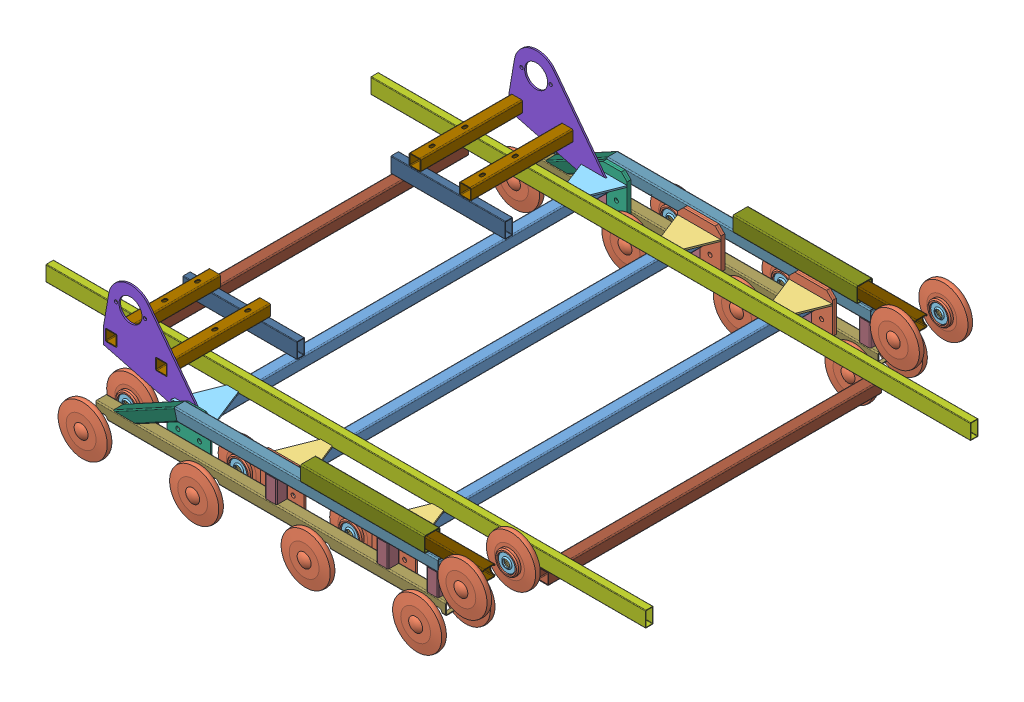
SolidWorks assembly ТП.016.001 - Рама гусеницы, configuration 00. Lengths in mm.
Overall size (1585 378.24 1275.68).
269 component instances, 35 part files, 9 mates.
Components (placement in the parent):
- ТП.016.01.01.01.00 - Рама корпуса-1: ТП.016.01.01.01.00 - Рама корпуса [00] x (-1 0 0) z (0 0 -1) size (1585 284.02 1098)
  - ТП.016.01.01.01.01.00 - Поперечная балка в сборе-1: ТП.016.01.01.01.01.00 - Поперечная балка в сборе [Центральная] at (824.8534 -30 544) size (112 110.77 1078)
    - ТП.016.01.01.01.01.01 - Поперечная балка (30х30)-1: ТП.016.01.01.01.01.01 - Поперечная балка (30х30) [--] at origin size (30 30 1068)
    - ТП.016.01.01.01.01.02 - Пластина кронштейна (5мм)-1: ТП.016.01.01.01.01.02 - Пластина кронштейна (5мм) [--] at (0 -56.7738 -5) size (112 110.77 5)
    - ТП.016.01.01.01.01.03 - Косынка верхняя (4мм)-1: ТП.016.01.01.01.01.03 - Косынка верхняя (4мм) [--] at (0 30 -10) size (112 4 104)
    - ТП.016.01.01.01.01.02 - Пластина кронштейна (5мм)-2: ТП.016.01.01.01.01.02 - Пластина кронштейна (5мм) [--] at (0 -56.7738 -1083) x (-1 0 0) z (0 0 -1) size (112 110.77 5)
    - ТП.016.01.01.01.01.03 - Косынка верхняя (4мм)-2: ТП.016.01.01.01.01.03 - Косынка верхняя (4мм) [--] at (0 30 -1078) x (-1 0 0) z (0 0 -1) size (112 4 104)
    - ТП.016.01.01.01.01.04 - Косынка нижняя (4мм)-2: ТП.016.01.01.01.01.04 - Косынка нижняя (4мм) [--] at (0 0 -1078) x (-1 0 0) z (0 0 -1) size (4 53.77 53.77)
    - ТП.016.01.01.01.01.04 - Косынка нижняя (4мм)-3: ТП.016.01.01.01.01.04 - Косынка нижняя (4мм) [--] at (0 0 -10) size (4 53.77 53.77)
    - ТП.016.01.01.01.01.05 - Пластина кронштейна задняя (5мм)-1: ТП.016.01.01.01.01.05 - Пластина кронштейна задняя (5мм) [--] at (0 -56.7738 -1083) x (-1 0 0) z (0 0 -1) size (112 110.77 5) (hidden)
    - ТП.016.01.01.01.01.06 - Косынка верхняя задняя (4мм)-1: ТП.016.01.01.01.01.06 - Косынка верхняя задняя (4мм) [--] at (-15 30 -1078) x (-1 0 0) z (0 0 -1) size (111.99 4 104) (hidden)
    - ТП.016.01.01.01.01.05 - Пластина кронштейна задняя (5мм)-2: ТП.016.01.01.01.01.05 - Пластина кронштейна задняя (5мм) [--] at (0 -56.7738 -10) x (-1 0 0) z (0 0 -1) size (112 110.77 5) (hidden)
    - ТП.016.01.01.01.01.06 - Косынка верхняя задняя (4мм)-2: ТП.016.01.01.01.01.06 - Косынка верхняя задняя (4мм) [--] at (-15 34 -10) x (-1 0 0) z (0 0 1) size (111.99 4 104) (hidden)
  - ТП.016.01.01.01.01.00 - Поперечная балка в сборе-2: ТП.016.01.01.01.01.00 - Поперечная балка в сборе [Центральная] at (536.5267 -30 544) size (112 110.77 1078)
    - ТП.016.01.01.01.01.01 - Поперечная балка (30х30)-1: ТП.016.01.01.01.01.01 - Поперечная балка (30х30) [--] at origin size (30 30 1068)
    - ТП.016.01.01.01.01.02 - Пластина кронштейна (5мм)-1: ТП.016.01.01.01.01.02 - Пластина кронштейна (5мм) [--] at (0 -56.7738 -5) size (112 110.77 5)
    - ТП.016.01.01.01.01.03 - Косынка верхняя (4мм)-1: ТП.016.01.01.01.01.03 - Косынка верхняя (4мм) [--] at (0 30 -10) size (112 4 104)
    - ТП.016.01.01.01.01.02 - Пластина кронштейна (5мм)-2: ТП.016.01.01.01.01.02 - Пластина кронштейна (5мм) [--] at (0 -56.7738 -1083) x (-1 0 0) z (0 0 -1) size (112 110.77 5)
    - ТП.016.01.01.01.01.03 - Косынка верхняя (4мм)-2: ТП.016.01.01.01.01.03 - Косынка верхняя (4мм) [--] at (0 30 -1078) x (-1 0 0) z (0 0 -1) size (112 4 104)
    - ТП.016.01.01.01.01.04 - Косынка нижняя (4мм)-2: ТП.016.01.01.01.01.04 - Косынка нижняя (4мм) [--] at (0 0 -1078) x (-1 0 0) z (0 0 -1) size (4 53.77 53.77)
    - ТП.016.01.01.01.01.04 - Косынка нижняя (4мм)-3: ТП.016.01.01.01.01.04 - Косынка нижняя (4мм) [--] at (0 0 -10) size (4 53.77 53.77)
    - ТП.016.01.01.01.01.05 - Пластина кронштейна задняя (5мм)-1: ТП.016.01.01.01.01.05 - Пластина кронштейна задняя (5мм) [--] at (0 -56.7738 -1083) x (-1 0 0) z (0 0 -1) size (112 110.77 5) (hidden)
    - ТП.016.01.01.01.01.06 - Косынка верхняя задняя (4мм)-1: ТП.016.01.01.01.01.06 - Косынка верхняя задняя (4мм) [--] at (-15 30 -1078) x (-1 0 0) z (0 0 -1) size (111.99 4 104) (hidden)
    - ТП.016.01.01.01.01.05 - Пластина кронштейна задняя (5мм)-2: ТП.016.01.01.01.01.05 - Пластина кронштейна задняя (5мм) [--] at (0 -56.7738 -10) x (-1 0 0) z (0 0 -1) size (112 110.77 5) (hidden)
    - ТП.016.01.01.01.01.06 - Косынка верхняя задняя (4мм)-2: ТП.016.01.01.01.01.06 - Косынка верхняя задняя (4мм) [--] at (-15 34 -10) x (-1 0 0) z (0 0 1) size (111.99 4 104) (hidden)
  - ТП.016.01.01.01.01.00 - Поперечная балка в сборе-3: ТП.016.01.01.01.01.00 - Поперечная балка в сборе [Задняя] at (1067.2668 -30 544) size (112 110.77 1078)
    - ТП.016.01.01.01.01.01 - Поперечная балка (30х30)-1: ТП.016.01.01.01.01.01 - Поперечная балка (30х30) [Под лебедку] at origin size (30 30 1068)
    - ТП.016.01.01.01.01.02 - Пластина кронштейна (5мм)-1: ТП.016.01.01.01.01.02 - Пластина кронштейна (5мм) [--] at (0 -56.7738 -5) size (112 110.77 5) (hidden)
    - ТП.016.01.01.01.01.03 - Косынка верхняя (4мм)-1: ТП.016.01.01.01.01.03 - Косынка верхняя (4мм) [--] at (0 30 -10) size (112 4 104) (hidden)
    - ТП.016.01.01.01.01.02 - Пластина кронштейна (5мм)-2: ТП.016.01.01.01.01.02 - Пластина кронштейна (5мм) [--] at (0 -56.7738 -1083) x (-1 0 0) z (0 0 -1) size (112 110.77 5) (hidden)
    - ТП.016.01.01.01.01.03 - Косынка верхняя (4мм)-2: ТП.016.01.01.01.01.03 - Косынка верхняя (4мм) [--] at (0 30 -1078) x (-1 0 0) z (0 0 -1) size (112 4 104) (hidden)
    - ТП.016.01.01.01.01.04 - Косынка нижняя (4мм)-2: ТП.016.01.01.01.01.04 - Косынка нижняя (4мм) [--] at (0 0 -1078) x (-1 0 0) z (0 0 -1) size (4 53.77 53.77)
    - ТП.016.01.01.01.01.04 - Косынка нижняя (4мм)-3: ТП.016.01.01.01.01.04 - Косынка нижняя (4мм) [--] at (0 0 -10) size (4 53.77 53.77)
    - ТП.016.01.01.01.01.05 - Пластина кронштейна задняя (5мм)-1: ТП.016.01.01.01.01.05 - Пластина кронштейна задняя (5мм) [--] at (0 -56.7738 -1083) x (-1 0 0) z (0 0 -1) size (112 110.77 5)
    - ТП.016.01.01.01.01.06 - Косынка верхняя задняя (4мм)-1: ТП.016.01.01.01.01.06 - Косынка верхняя задняя (4мм) [--] at (-15 30 -1078) x (-1 0 0) z (0 0 -1) size (111.99 4 104)
    - ТП.016.01.01.01.01.05 - Пластина кронштейна задняя (5мм)-2: ТП.016.01.01.01.01.05 - Пластина кронштейна задняя (5мм) [--] at (0 -56.7738 -10) x (-1 0 0) z (0 0 -1) size (112 110.77 5)
    - ТП.016.01.01.01.01.06 - Косынка верхняя задняя (4мм)-2: ТП.016.01.01.01.01.06 - Косынка верхняя задняя (4мм) [--] at (-15 34 -10) x (-1 0 0) z (0 0 1) size (111.99 4 104)
  - ТП.016.01.01.01.02 - Балка платформы боковая (40х20)-1: ТП.016.01.01.01.02 - Балка платформы боковая (40х20) [--] at (250 0 -420) x (0 0 -1) z (1 0 0) size (20 40 1550)
  - ТП.016.01.01.01.02 - Балка платформы боковая (40х20)-2: ТП.016.01.01.01.02 - Балка платформы боковая (40х20) [--] at (250 0 420) x (0 0 -1) z (1 0 0) size (20 40 1550)
  - Схема рамы ЭСКИЗ-1: Схема рамы ЭСКИЗ [--] x (0 0 -1) z (1 0 0) size (559 0 1052.27)
  - ТП.016.01.01.01.03.00 - Опора редуктора-1: ТП.016.01.01.01.03.00 - Опора редуктора [Правая] at (1235 143.2262 -526.5) x (-1 0 0) z (0 0 -1) size (276.73 227.25 267.34)
    - ТП.016.01.01.01.03.01 - Щека ведущей оси (4мм)-1: ТП.016.01.01.01.03.01 - Щека ведущей оси (4мм) [--] at origin size (249.73 227.25 4)
    - ТП.016.01.01.01.03.02 - Балка опоры ребуктора (30х30)-1: ТП.016.01.01.01.03.02 - Балка опоры ребуктора (30х30) [--] at (65 -72 0) size (30 30 267.34)
    - ТП.016.01.01.01.03.02 - Балка опоры ребуктора (30х30)-2: ТП.016.01.01.01.03.02 - Балка опоры ребуктора (30х30) [--] at (-65 -72 0) size (30 30 267.34)
    - ТП.016.01.01.01.03.02 - Балка опоры ребуктора (30х30)-3: ТП.016.01.01.01.03.02 - Балка опоры ребуктора (30х30) [--] at (95 -72 -4) x (-1 0 0) z (0 0 -1) size (30 30 267.34) (hidden)
    - ТП.016.01.01.01.03.02 - Балка опоры ребуктора (30х30)-4: ТП.016.01.01.01.03.02 - Балка опоры ребуктора (30х30) [--] at (-35 -72 -4) x (-1 0 0) z (0 0 -1) size (30 30 267.34) (hidden)
    - ТП.016.01.01.01.03.03 - Пол под редуктор (3мм)-1: ТП.016.01.01.01.03.03 - Пол под редуктор (3мм) [--] at (65 -143.2262 -181.9182) x (0 0 -1) z (1 0 0) size (130.84 76.23 264.73)
  - ТП.016.01.01.01.03.00 - Опора редуктора-2: ТП.016.01.01.01.03.00 - Опора редуктора [Левая] at (1235 143.2262 522.5) x (-1 0 0) z (0 0 -1) size (276.73 227.25 267.34)
    - ТП.016.01.01.01.03.01 - Щека ведущей оси (4мм)-1: ТП.016.01.01.01.03.01 - Щека ведущей оси (4мм) [--] at origin size (249.73 227.25 4)
    - ТП.016.01.01.01.03.02 - Балка опоры ребуктора (30х30)-1: ТП.016.01.01.01.03.02 - Балка опоры ребуктора (30х30) [--] at (65 -72 0) size (30 30 267.34) (hidden)
    - ТП.016.01.01.01.03.02 - Балка опоры ребуктора (30х30)-2: ТП.016.01.01.01.03.02 - Балка опоры ребуктора (30х30) [--] at (-65 -72 0) size (30 30 267.34) (hidden)
    - ТП.016.01.01.01.03.02 - Балка опоры ребуктора (30х30)-3: ТП.016.01.01.01.03.02 - Балка опоры ребуктора (30х30) [--] at (95 -72 -4) x (-1 0 0) z (0 0 -1) size (30 30 267.34)
    - ТП.016.01.01.01.03.02 - Балка опоры ребуктора (30х30)-4: ТП.016.01.01.01.03.02 - Балка опоры ребуктора (30х30) [--] at (-35 -72 -4) x (-1 0 0) z (0 0 -1) size (30 30 267.34)
    - ТП.016.01.01.01.03.03 - Пол под редуктор (3мм)-1: ТП.016.01.01.01.03.03 - Пол под редуктор (3мм) [--] at (65 -143.2262 177.9182) x (0 0 -1) z (1 0 0) size (130.84 76.23 264.73)
  - ТП.016.01.01.01.04 - Опора короткая под редуктор (40х20)-1: ТП.016.01.01.01.04 - Опора короткая под редуктор (40х20) [--] at (1052.2668 0 -259.1637) x (0 0 -1) z (1 0 0) size (20 40 294.73)
  - ТП.016.01.01.01.04 - Опора короткая под редуктор (40х20)-2: ТП.016.01.01.01.04 - Опора короткая под редуктор (40х20) [--] at (1052.2668 0 279.1637) x (0 0 -1) z (1 0 0) size (20 40 294.73)
  - ТП.016.01.01.01.05 - Поперечина короткая (30х30)-1: ТП.016.01.01.01.05 - Поперечина короткая (30х30) [--] at (1347 0 0) size (30 30 860)
  - ТП.016.01.01.01.05 - Поперечина короткая (30х30)-2: ТП.016.01.01.01.05 - Поперечина короткая (30х30) [--] at (280 0 0) size (30 30 860)
  - ТП.016.01.01.01.06 - Поддержка центральная (40х20)-1: ТП.016.01.01.01.06 - Поддержка центральная (40х20) [--] at (45 -9.1741 -23) x (0 0 1) z (-1 0 0) size (20 40 596.53)
  - ТП.016.01.01.01.06 - Поддержка центральная (40х20)-2: ТП.016.01.01.01.06 - Поддержка центральная (40х20) [--] at (45 -9.1741 43) x (0 0 1) z (-1 0 0) size (20 40 596.53)
  - ТП.016.01.01.01.07 - Пол перед (3мм)-1: ТП.016.01.01.01.07 - Пол перед (3мм) [Правый] at (0 0 -410) x (0 0 -1) z (1 0 0) size (377 29.49 517.11)
  - ТП.016.01.01.01.07 - Пол перед (3мм)-2: ТП.016.01.01.01.07 - Пол перед (3мм) [Левый] at (0 0 -344) x (0 0 -1) z (1 0 0) size (754 29.49 517.11)
  - ТП.016.01.01.01.08 - Пол центр (2мм)-1: ТП.016.01.01.01.08 - Пол центр (2мм) [--] at (250 0 0) x (0 0 -1) z (1 0 0) size (820 12 817.27)
  - ТП.016.01.01.01.09 - Задний бампер (40х20)-1: ТП.016.01.01.01.09 - Задний бампер (40х20) [--] at (1570 0 0) size (20 40 860)
  - ТП.016.01.01.01.10 - Пол капота (3мм)-1: ТП.016.01.01.01.10 - Пол капота (3мм) [--] at (1550 0 0) x (0 0 1) z (-1 0 0) size (820 13 482.73)
  - Гайка (ГОСТ ISO 4032-2014)-1: Гайка (ГОСТ ISO 4032-2014) [Гайка М6 (ГОСТ ISO 4032)] at (153.1386 -2.6 64.0253) x (-0.998033 0 -0.062689) z (0 1 0) size (10 11.05 5.2)
  - Гайка (ГОСТ ISO 4032-2014)-2: Гайка (ГОСТ ISO 4032-2014) [Гайка М6 (ГОСТ ISO 4032)] at (403.0634 -2.6 70.156) x (-0.991964 0 0.126519) z (0 1 0) size (10 11.05 5.2)
  - Гайка (ГОСТ ISO 4032-2014)-3: Гайка (ГОСТ ISO 4032-2014) [Гайка М6 (ГОСТ ISO 4032)] at (672.9822 -2.6 76.7772) x (-0.941367 0 0.337385) z (0 1 0) size (10 11.05 5.2)
  - Гайка (ГОСТ ISO 4032-2014)-4: Гайка (ГОСТ ISO 4032-2014) [Гайка М6 (ГОСТ ISO 4032)] at (1021.6211 -2.6 85.3294) x (-0.83604 0 0.548669) z (0 1 0) size (10 11.05 5.2)
  - Гайка (ГОСТ ISO 4032-2014)-5: Гайка (ГОСТ ISO 4032-2014) [Гайка М6 (ГОСТ ISO 4032)] at (1021.6211 -2.6 -85.3294) x (-0.680834 0 0.732437) z (0 1 0) size (10 11.05 5.2)
  - Гайка (ГОСТ ISO 4032-2014)-6: Гайка (ГОСТ ISO 4032-2014) [Гайка М6 (ГОСТ ISO 4032)] at (672.9822 -2.6 -76.7772) x (-0.498939 0 0.866637) z (0 1 0) size (10 11.05 5.2)
  - Гайка (ГОСТ ISO 4032-2014)-7: Гайка (ГОСТ ISO 4032-2014) [Гайка М6 (ГОСТ ISO 4032)] at (403.0634 -2.6 -70.156) x (-0.323185 0 0.946336) z (0 1 0) size (10 11.05 5.2)
  - Гайка (ГОСТ ISO 4032-2014)-8: Гайка (ГОСТ ISO 4032-2014) [Гайка М6 (ГОСТ ISO 4032)] at (153.1386 -2.6 -64.0253) x (-0.182176 0 0.983266) z (0 1 0) size (10 11.05 5.2)
- ТП.016.02.00 - Гусеничный модуль в сборе-1: ТП.016.02.00 - Гусеничный модуль в сборе [Левый] at (-392.3634 -86.7738 -559) x (-1 0 0) z (0 0 -1) size (1147.02 302.71 157.68)
  - ТП.016.02.01.00 - Модуль гусеницы силовой-1: ТП.016.02.01.00 - Модуль гусеницы силовой [Левый] at origin size (904.98 176.07 133.68)
    - ТП.016.02.01.01.00 - Рама гусеницы с осями-1: ТП.016.02.01.01.00 - Рама гусеницы с осями [00] at origin size (904.98 176.07 133.68)
      - ТП.016.02.01.01.01 - Нижняя балка гуленицы (30х30)-1: ТП.016.02.01.01.01 - Нижняя балка гуленицы (30х30) [--] at origin size (904.98 30 30)
      - ТП.016.02.01.01.02(02) - Ось цельная 21_3мм-1: ТП.016.02.01.01.02(02) - Ось цельная 21_3мм [--] x (0 0 1) z (-1 0 0) size (133.68 21.3 21.3)
      - ТП.016.02.01.01.02(02) - Ось цельная 21_3мм-2: ТП.016.02.01.01.02(02) - Ось цельная 21_3мм [--] at (288.3267 0 0) x (0 0 1) z (-0.987351 0.158553 0) size (133.68 21.3 21.3)
      - ТП.016.02.01.01.02(02) - Ось цельная 21_3мм-3: ТП.016.02.01.01.02(02) - Ось цельная 21_3мм [--] at (576.6534 0 0) x (0 0 1) z (-0.959125 0.282984 0) size (133.68 21.3 21.3)
      - ТП.016.02.01.01.02(02) - Ось цельная 21_3мм-4: ТП.016.02.01.01.02(02) - Ось цельная 21_3мм [--] at (864.9801 0 0) x (0 0 1) z (-0.928571 0.371154 0) size (133.68 21.3 21.3)
      - ТП.016.02.01.01.03 - Связка балок гусеничного модуля-1: ТП.016.02.01.01.03 - Связка балок гусеничного модуля [--] at (0 86.7738 0) x (-1 0 0) z (0 0 -1) size (30 56.77 30)
      - ТП.016.02.01.01.03 - Связка балок гусеничного модуля-2: ТП.016.02.01.01.03 - Связка балок гусеничного модуля [--] at (129.1634 86.7738 0) x (-1 0 0) z (0 0 -1) size (30 56.77 30)
      - ТП.016.02.01.01.03 - Связка балок гусеничного модуля-3: ТП.016.02.01.01.03 - Связка балок гусеничного модуля [--] at (417.4901 86.7738 0) x (-1 0 0) z (0 0 -1) size (30 56.77 30)
      - ТП.016.02.01.01.04 - Верхняя балка рамы гусеницы-1: ТП.016.02.01.01.04 - Верхняя балка рамы гусеницы [--] at (0 136.7738 0) x (0 0 1) z (-1 0 0) size (30 30 682.14)
      - ТП.016.02.01.01.05 - Задняя косая-1: ТП.016.02.01.01.05 - Задняя косая [--] at (864.9801 0 -15) x (0 0 -1) z (0.877984 -0.478691 0) size (30 30 181.27)
      - ТП.016.02.01.01.06.00 - Стакан натяжителя-1: ТП.016.02.01.01.06.00 - Стакан натяжителя [00] at (30 136.7738 0) x (-1 0 0) z (0 0 -1) size (320 50.91 50.91)
        - ТП.016.02.01.01.06.01 - Рубашка штока ролика натяжного-1: ТП.016.02.01.01.06.01 - Рубашка штока ролика натяжного [--] at origin size (320 40 40)
        - ТП.016.02.01.01.06.02 - Гайка рубашки штока-1: ТП.016.02.01.01.06.02 - Гайка рубашки штока [--] at (-320 0 0) x (0 -0.713098 -0.701064) z (1 0 0) size (36 36 20)
    - ТП.016.01.01.01.01.02 - Пластина кронштейна (5мм)-1: ТП.016.01.01.01.01.02 - Пластина кронштейна (5мм) [--] at (144.1634 0 20) size (112 110.77 5) (hidden)
    - ТП.016.01.01.01.01.02 - Пластина кронштейна (5мм)-2: ТП.016.01.01.01.01.02 - Пластина кронштейна (5мм) [--] at (432.4901 0 20) size (112 110.77 5) (hidden)
    - ТП.016.01.01.01.01.05 - Пластина кронштейна задняя (5мм)-1: ТП.016.01.01.01.01.05 - Пластина кронштейна задняя (5мм) [--] at (674.9034 0 15) x (-1 0 0) z (0 0 -1) size (112 110.77 5) (hidden)
    - ТП.016.01.01.01.01.02 - Пластина кронштейна (5мм)-4: ТП.016.01.01.01.01.02 - Пластина кронштейна (5мм) [--] at (144.1634 0 -20) x (-1 0 0) z (0 0 -1) size (112 110.77 5)
    - ТП.016.01.01.01.01.02 - Пластина кронштейна (5мм)-6: ТП.016.01.01.01.01.02 - Пластина кронштейна (5мм) [--] at (432.4901 0 -20) x (-1 0 0) z (0 0 -1) size (112 110.77 5)
    - ТП.016.01.01.01.01.05 - Пластина кронштейна задняя (5мм)-2: ТП.016.01.01.01.01.05 - Пластина кронштейна задняя (5мм) [--] at (674.9034 0 -20) x (-1 0 0) z (0 0 -1) size (112 110.77 5)
  - ТП.016.02.02.00 - Натяжитель гусеницы-1: ТП.016.02.02.00 - Натяжитель гусеницы [00] at (-117 136.7738 0) x (-1 0 0) z (0 0 1) size (371.74 149.44 157.68)
    - ТП.016.02.02.01.00 - Толкатель натяжки-1: ТП.016.02.02.01.00 - Толкатель натяжки [00] at origin size (311.12 30 133.68)
      - ТП.016.02.02.01.01 - Шток натяжного ролика (30х30)-1: ТП.016.02.02.01.01 - Шток натяжного ролика (30х30) [--] at origin size (297.02 30 30)
      - ТП.016.02.01.01.02(02) - Ось цельная 21_3мм-1: ТП.016.02.01.01.02(02) - Ось цельная 21_3мм [--] x (0 0 1) z (-0.910058 0.41448 0) size (133.68 21.3 21.3)
      - ТП.016.02.02.01.02 - Заглушка штока-1: ТП.016.02.02.01.02 - Заглушка штока [--] at (-297.0168 0 0) x (0 -1 0) z (1 0 0) size (26 26 20)
    - Каток 129(47) в сборе-1: Каток 129(47) в сборе [00] at (0 0 62.8416) x (0 0 1) z (1 0 0) size (35.7 129 129)
      - Каток 129(47)-1: Каток 129(47) [--] at origin size (35 129 129)
      - Подшипник ГОСТ 8338-75 -1: Подшипник ГОСТ 8338-75  [Подшипник 204 ГОСТ 8338-75] at (-1 0 0) x (1 0 0) z (0 -0.327433 -0.944874) size (14 47 47)
      - Стопор внутренний до 165мм (ГОСТ 13943-86)-1: Стопор внутренний до 165мм (ГОСТ 13943-86) [Кольцо 47] at (-8 0 0) x (0 0.910839 0.412761) z (-1 0 0) size (49.5 51.2 1.7)
      - Сальник 47х20-1: Сальник 47х20 [--] at (-9.7 0 0) x (-1 0 0) z (0 0.937697 -0.347453) size (10 47 47)
    - Каток 129(47) в сборе-2: Каток 129(47) в сборе [00] at (0 0 -62.8416) x (0 0 -1) z (-0.173648 0.984808 0) size (35.7 129 129)
      - Каток 129(47)-1: Каток 129(47) [--] at origin size (35 129 129)
      - Подшипник ГОСТ 8338-75 -1: Подшипник ГОСТ 8338-75  [Подшипник 204 ГОСТ 8338-75] at (-1 0 0) x (1 0 0) z (0 -0.327433 -0.944874) size (14 47 47)
      - Стопор внутренний до 165мм (ГОСТ 13943-86)-1: Стопор внутренний до 165мм (ГОСТ 13943-86) [Кольцо 47] at (-8 0 0) x (0 0.910839 0.412761) z (-1 0 0) size (49.5 51.2 1.7)
      - Сальник 47х20-1: Сальник 47х20 [--] at (-9.7 0 0) x (-1 0 0) z (0 0.937697 -0.347453) size (10 47 47)
    - ТП.016.02.02.02 - Шайба оси-1: ТП.016.02.02.02 - Шайба оси [--] at (0 0 -66.3614) x (0 0 1) z (0.48394 0.875101 0) size (4 24 24)
    - Болты с шестигранной головкой кт.В (ГОСТ 7798-70)-1: Болты с шестигранной головкой кт.В (ГОСТ 7798-70) [Болт М6-6gx14(S10) ГОСТ 7798-77] at (0 0 -69.3416) x (0 0 1) z (0.143998 -0.989578 0) size (18 10.9 10)
    - ТП.016.02.02.02 - Шайба оси-2: ТП.016.02.02.02 - Шайба оси [--] at (0 0 66.3614) x (0 0 -1) z (0.777771 0.628548 0) size (4 24 24)
    - Болты с шестигранной головкой кт.В (ГОСТ 7798-70)-2: Болты с шестигранной головкой кт.В (ГОСТ 7798-70) [Болт М6-6gx14(S10) ГОСТ 7798-77] at (0 0 69.3416) x (0 0 -1) z (-0.999549 -0.030028 0) size (18 10.9 10)
  - ТП.016.02.03 - Винт натяжителя-1: ТП.016.02.03 - Винт натяжителя [--] at (350.0168 136.7738 0) x (0 -0.01927 -0.999814) z (-1 0 0) size (20 20 231.35)
  - Каток 129(47) в сборе-1: Каток 129(47) в сборе [00] at (0 0 -62.8416) x (0 0 -1) z (-0.261474 0.96521 0) size (35.7 129 129)
    - Каток 129(47)-1: Каток 129(47) [--] at origin size (35 129 129)
    - Подшипник ГОСТ 8338-75 -1: Подшипник ГОСТ 8338-75  [Подшипник 204 ГОСТ 8338-75] at (-1 0 0) x (1 0 0) z (0 -0.327433 -0.944874) size (14 47 47)
    - Стопор внутренний до 165мм (ГОСТ 13943-86)-1: Стопор внутренний до 165мм (ГОСТ 13943-86) [Кольцо 47] at (-8 0 0) x (0 0.910839 0.412761) z (-1 0 0) size (49.5 51.2 1.7)
    - Сальник 47х20-1: Сальник 47х20 [--] at (-9.7 0 0) x (-1 0 0) z (0 0.937697 -0.347453) size (10 47 47)
  - Каток 129(47) в сборе-2: Каток 129(47) в сборе [00] at (288.3267 0 -62.8416) x (0 0 -1) z (-0.411203 0.911544 0) size (35.7 129 129)
    - Каток 129(47)-1: Каток 129(47) [--] at origin size (35 129 129)
    - Подшипник ГОСТ 8338-75 -1: Подшипник ГОСТ 8338-75  [Подшипник 204 ГОСТ 8338-75] at (-1 0 0) x (1 0 0) z (0 -0.327433 -0.944874) size (14 47 47)
    - Стопор внутренний до 165мм (ГОСТ 13943-86)-1: Стопор внутренний до 165мм (ГОСТ 13943-86) [Кольцо 47] at (-8 0 0) x (0 0.910839 0.412761) z (-1 0 0) size (49.5 51.2 1.7)
    - Сальник 47х20-1: Сальник 47х20 [--] at (-9.7 0 0) x (-1 0 0) z (0 0.937697 -0.347453) size (10 47 47)
  - Каток 129(47) в сборе-4: Каток 129(47) в сборе [00] at (576.6534 0 -62.8416) x (0 0 -1) z (-0.523925 0.851764 0) size (35.7 129 129)
    - Каток 129(47)-1: Каток 129(47) [--] at origin size (35 129 129)
    - Подшипник ГОСТ 8338-75 -1: Подшипник ГОСТ 8338-75  [Подшипник 204 ГОСТ 8338-75] at (-1 0 0) x (1 0 0) z (0 -0.327433 -0.944874) size (14 47 47)
    - Стопор внутренний до 165мм (ГОСТ 13943-86)-1: Стопор внутренний до 165мм (ГОСТ 13943-86) [Кольцо 47] at (-8 0 0) x (0 0.910839 0.412761) z (-1 0 0) size (49.5 51.2 1.7)
    - Сальник 47х20-1: Сальник 47х20 [--] at (-9.7 0 0) x (-1 0 0) z (0 0.937697 -0.347453) size (10 47 47)
  - Каток 129(47) в сборе-6: Каток 129(47) в сборе [00] at (864.9801 0 -62.8416) x (0 0 -1) z (0.601039 -0.79922 0) size (35.7 129 129)
    - Каток 129(47)-1: Каток 129(47) [--] at origin size (35 129 129)
    - Подшипник ГОСТ 8338-75 -1: Подшипник ГОСТ 8338-75  [Подшипник 204 ГОСТ 8338-75] at (-1 0 0) x (1 0 0) z (0 -0.327433 -0.944874) size (14 47 47)
    - Стопор внутренний до 165мм (ГОСТ 13943-86)-1: Стопор внутренний до 165мм (ГОСТ 13943-86) [Кольцо 47] at (-8 0 0) x (0 0.910839 0.412761) z (-1 0 0) size (49.5 51.2 1.7)
    - Сальник 47х20-1: Сальник 47х20 [--] at (-9.7 0 0) x (-1 0 0) z (0 0.937697 -0.347453) size (10 47 47)
  - Каток 129(47) в сборе-8: Каток 129(47) в сборе [00] at (864.9801 0 62.8416) x (0 0 1) z (0.907466 0.420125 0) size (35.7 129 129)
    - Каток 129(47)-1: Каток 129(47) [--] at origin size (35 129 129)
    - Подшипник ГОСТ 8338-75 -1: Подшипник ГОСТ 8338-75  [Подшипник 204 ГОСТ 8338-75] at (-1 0 0) x (1 0 0) z (0 -0.327433 -0.944874) size (14 47 47)
    - Стопор внутренний до 165мм (ГОСТ 13943-86)-1: Стопор внутренний до 165мм (ГОСТ 13943-86) [Кольцо 47] at (-8 0 0) x (0 0.910839 0.412761) z (-1 0 0) size (49.5 51.2 1.7)
    - Сальник 47х20-1: Сальник 47х20 [--] at (-9.7 0 0) x (-1 0 0) z (0 0.937697 -0.347453) size (10 47 47)
  - Каток 129(47) в сборе-10: Каток 129(47) в сборе [00] at (576.6534 0 62.8416) x (0 0 1) z (0.820726 0.571322 0) size (35.7 129 129)
    - Каток 129(47)-1: Каток 129(47) [--] at origin size (35 129 129)
    - Подшипник ГОСТ 8338-75 -1: Подшипник ГОСТ 8338-75  [Подшипник 204 ГОСТ 8338-75] at (-1 0 0) x (1 0 0) z (0 -0.327433 -0.944874) size (14 47 47)
    - Стопор внутренний до 165мм (ГОСТ 13943-86)-1: Стопор внутренний до 165мм (ГОСТ 13943-86) [Кольцо 47] at (-8 0 0) x (0 0.910839 0.412761) z (-1 0 0) size (49.5 51.2 1.7)
    - Сальник 47х20-1: Сальник 47х20 [--] at (-9.7 0 0) x (-1 0 0) z (0 0.937697 -0.347453) size (10 47 47)
  - Каток 129(47) в сборе-12: Каток 129(47) в сборе [00] at (288.3267 0 62.8416) x (0 0 1) z (0.709048 0.70516 0) size (35.7 129 129)
    - Каток 129(47)-1: Каток 129(47) [--] at origin size (35 129 129)
    - Подшипник ГОСТ 8338-75 -1: Подшипник ГОСТ 8338-75  [Подшипник 204 ГОСТ 8338-75] at (-1 0 0) x (1 0 0) z (0 -0.327433 -0.944874) size (14 47 47)
    - Стопор внутренний до 165мм (ГОСТ 13943-86)-1: Стопор внутренний до 165мм (ГОСТ 13943-86) [Кольцо 47] at (-8 0 0) x (0 0.910839 0.412761) z (-1 0 0) size (49.5 51.2 1.7)
    - Сальник 47х20-1: Сальник 47х20 [--] at (-9.7 0 0) x (-1 0 0) z (0 0.937697 -0.347453) size (10 47 47)
  - Каток 129(47) в сборе-14: Каток 129(47) в сборе [00] at (0 0 62.8416) x (0 0 1) z (0.575827 0.817572 0) size (35.7 129 129)
    - Каток 129(47)-1: Каток 129(47) [--] at origin size (35 129 129)
    - Подшипник ГОСТ 8338-75 -1: Подшипник ГОСТ 8338-75  [Подшипник 204 ГОСТ 8338-75] at (-1 0 0) x (1 0 0) z (0 -0.327433 -0.944874) size (14 47 47)
    - Стопор внутренний до 165мм (ГОСТ 13943-86)-1: Стопор внутренний до 165мм (ГОСТ 13943-86) [Кольцо 47] at (-8 0 0) x (0 0.910839 0.412761) z (-1 0 0) size (49.5 51.2 1.7)
    - Сальник 47х20-1: Сальник 47х20 [--] at (-9.7 0 0) x (-1 0 0) z (0 0.937697 -0.347453) size (10 47 47)
  - ТП.016.02.02.02 - Шайба оси-1: ТП.016.02.02.02 - Шайба оси [--] at (0 0 -66.3614) x (0 0 1) z (0.502694 0.864464 0) size (4 24 24)
  - Болты с шестигранной головкой кт.В (ГОСТ 7798-70)-1: Болты с шестигранной головкой кт.В (ГОСТ 7798-70) [Болт М6-6gx16(S10) ГОСТ 7798-77] at (0 0 -69.3416) x (0 0 1) z (0.899536 0.436848 0) size (20 10.9 10)
  - ТП.016.02.02.02 - Шайба оси-2: ТП.016.02.02.02 - Шайба оси [--] at (288.3267 0 -66.3614) x (0 0 1) z (0.359272 0.933233 0) size (4 24 24)
  - Болты с шестигранной головкой кт.В (ГОСТ 7798-70)-2: Болты с шестигранной головкой кт.В (ГОСТ 7798-70) [Болт М6-6gx16(S10) ГОСТ 7798-77] at (288.3267 0 -69.3416) x (0 0 1) z (0.818894 0.573945 0) size (20 10.9 10)
  - ТП.016.02.02.02 - Шайба оси-4: ТП.016.02.02.02 - Шайба оси [--] at (576.6534 0 -66.3614) x (0 0 1) z (0.237517 0.971383 0) size (4 24 24)
  - Болты с шестигранной головкой кт.В (ГОСТ 7798-70)-4: Болты с шестигранной головкой кт.В (ГОСТ 7798-70) [Болт М6-6gx16(S10) ГОСТ 7798-77] at (576.6534 0 -69.3416) x (0 0 1) z (0.739146 0.673545 0) size (20 10.9 10)
  - ТП.016.02.02.02 - Шайба оси-6: ТП.016.02.02.02 - Шайба оси [--] at (864.9801 0 -66.3614) x (0 0 1) z (0.145939 0.989294 0) size (4 24 24)
  - Болты с шестигранной головкой кт.В (ГОСТ 7798-70)-6: Болты с шестигранной головкой кт.В (ГОСТ 7798-70) [Болт М6-6gx16(S10) ГОСТ 7798-77] at (864.9801 0 -69.3416) x (0 0 1) z (0.673145 0.73951 0) size (20 10.9 10)
  - ТП.016.02.02.02 - Шайба оси-8: ТП.016.02.02.02 - Шайба оси [--] at (864.9801 0 66.3614) x (0 0 -1) z (0.339092 0.940753 0) size (4 24 24)
  - Болты с шестигранной головкой кт.В (ГОСТ 7798-70)-8: Болты с шестигранной головкой кт.В (ГОСТ 7798-70) [Болт М6-6gx16(S10) ГОСТ 7798-77] at (864.9801 0 69.3416) x (0 0 -1) z (-0.243566 0.969884 0) size (20 10.9 10)
  - ТП.016.02.02.02 - Шайба оси-11: ТП.016.02.02.02 - Шайба оси [--] at (576.6534 0 66.3614) x (0 0 -1) z (0.170581 0.985344 0) size (4 24 24)
  - Болты с шестигранной головкой кт.В (ГОСТ 7798-70)-11: Болты с шестигранной головкой кт.В (ГОСТ 7798-70) [Болт М6-6gx16(S10) ГОСТ 7798-77] at (576.6534 0 69.3416) x (0 0 -1) z (-0.408284 0.912855 0) size (20 10.9 10)
  - ТП.016.02.02.02 - Шайба оси-13: ТП.016.02.02.02 - Шайба оси [--] at (288.3267 0 66.3614) x (0 0 -1) z (-0.003114 0.999995 0) size (4 24 24)
  - Болты с шестигранной головкой кт.В (ГОСТ 7798-70)-13: Болты с шестигранной головкой кт.В (ГОСТ 7798-70) [Болт М6-6gx16(S10) ГОСТ 7798-77] at (288.3267 0 69.3416) x (0 0 -1) z (-0.560597 0.828089 0) size (20 10.9 10)
  - ТП.016.02.02.02 - Шайба оси-15: ТП.016.02.02.02 - Шайба оси [--] at (0 0 66.3614) x (0 0 -1) z (-0.176714 0.984262 0) size (4 24 24)
  - Болты с шестигранной головкой кт.В (ГОСТ 7798-70)-15: Болты с шестигранной головкой кт.В (ГОСТ 7798-70) [Болт М6-6gx16(S10) ГОСТ 7798-77] at (0 0 69.3416) x (0 0 -1) z (-0.695876 0.718162 0) size (20 10.9 10)
- ТП.016.02.00 - Гусеничный модуль в сборе-2: ТП.016.02.00 - Гусеничный модуль в сборе [Правый] at (-392.3634 -86.7738 559) x (-1 0 0) z (0 0 -1) size (1147.02 302.71 157.68)
  - ТП.016.02.01.00 - Модуль гусеницы силовой-1: ТП.016.02.01.00 - Модуль гусеницы силовой [Правый] at origin size (904.98 176.07 133.68)
    - ТП.016.02.01.01.00 - Рама гусеницы с осями-1: ТП.016.02.01.01.00 - Рама гусеницы с осями [00] at origin size (904.98 176.07 133.68)
      - ТП.016.02.01.01.01 - Нижняя балка гуленицы (30х30)-1: ТП.016.02.01.01.01 - Нижняя балка гуленицы (30х30) [--] at origin size (904.98 30 30)
      - ТП.016.02.01.01.02(02) - Ось цельная 21_3мм-1: ТП.016.02.01.01.02(02) - Ось цельная 21_3мм [--] x (0 0 1) z (-1 0 0) size (133.68 21.3 21.3)
      - ТП.016.02.01.01.02(02) - Ось цельная 21_3мм-2: ТП.016.02.01.01.02(02) - Ось цельная 21_3мм [--] at (288.3267 0 0) x (0 0 1) z (-0.987351 0.158553 0) size (133.68 21.3 21.3)
      - ТП.016.02.01.01.02(02) - Ось цельная 21_3мм-3: ТП.016.02.01.01.02(02) - Ось цельная 21_3мм [--] at (576.6534 0 0) x (0 0 1) z (-0.959125 0.282984 0) size (133.68 21.3 21.3)
      - ТП.016.02.01.01.02(02) - Ось цельная 21_3мм-4: ТП.016.02.01.01.02(02) - Ось цельная 21_3мм [--] at (864.9801 0 0) x (0 0 1) z (-0.928571 0.371154 0) size (133.68 21.3 21.3)
      - ТП.016.02.01.01.03 - Связка балок гусеничного модуля-1: ТП.016.02.01.01.03 - Связка балок гусеничного модуля [--] at (0 86.7738 0) x (-1 0 0) z (0 0 -1) size (30 56.77 30)
      - ТП.016.02.01.01.03 - Связка балок гусеничного модуля-2: ТП.016.02.01.01.03 - Связка балок гусеничного модуля [--] at (129.1634 86.7738 0) x (-1 0 0) z (0 0 -1) size (30 56.77 30)
      - ТП.016.02.01.01.03 - Связка балок гусеничного модуля-3: ТП.016.02.01.01.03 - Связка балок гусеничного модуля [--] at (417.4901 86.7738 0) x (-1 0 0) z (0 0 -1) size (30 56.77 30)
      - ТП.016.02.01.01.04 - Верхняя балка рамы гусеницы-1: ТП.016.02.01.01.04 - Верхняя балка рамы гусеницы [--] at (0 136.7738 0) x (0 0 1) z (-1 0 0) size (30 30 682.14)
      - ТП.016.02.01.01.05 - Задняя косая-1: ТП.016.02.01.01.05 - Задняя косая [--] at (864.9801 0 -15) x (0 0 -1) z (0.877984 -0.478691 0) size (30 30 181.27)
      - ТП.016.02.01.01.06.00 - Стакан натяжителя-1: ТП.016.02.01.01.06.00 - Стакан натяжителя [00] at (30 136.7738 0) x (-1 0 0) z (0 0 -1) size (320 50.91 50.91)
        - ТП.016.02.01.01.06.01 - Рубашка штока ролика натяжного-1: ТП.016.02.01.01.06.01 - Рубашка штока ролика натяжного [--] at origin size (320 40 40)
        - ТП.016.02.01.01.06.02 - Гайка рубашки штока-1: ТП.016.02.01.01.06.02 - Гайка рубашки штока [--] at (-320 0 0) x (0 -0.713098 -0.701064) z (1 0 0) size (36 36 20)
    - ТП.016.01.01.01.01.02 - Пластина кронштейна (5мм)-1: ТП.016.01.01.01.01.02 - Пластина кронштейна (5мм) [--] at (144.1634 0 20) size (112 110.77 5)
    - ТП.016.01.01.01.01.02 - Пластина кронштейна (5мм)-2: ТП.016.01.01.01.01.02 - Пластина кронштейна (5мм) [--] at (432.4901 0 20) size (112 110.77 5)
    - ТП.016.01.01.01.01.05 - Пластина кронштейна задняя (5мм)-1: ТП.016.01.01.01.01.05 - Пластина кронштейна задняя (5мм) [--] at (674.9034 0 15) x (-1 0 0) z (0 0 -1) size (112 110.77 5)
    - ТП.016.01.01.01.01.02 - Пластина кронштейна (5мм)-4: ТП.016.01.01.01.01.02 - Пластина кронштейна (5мм) [--] at (144.1634 0 -20) x (-1 0 0) z (0 0 -1) size (112 110.77 5) (hidden)
    - ТП.016.01.01.01.01.02 - Пластина кронштейна (5мм)-6: ТП.016.01.01.01.01.02 - Пластина кронштейна (5мм) [--] at (432.4901 0 -20) x (-1 0 0) z (0 0 -1) size (112 110.77 5) (hidden)
    - ТП.016.01.01.01.01.05 - Пластина кронштейна задняя (5мм)-2: ТП.016.01.01.01.01.05 - Пластина кронштейна задняя (5мм) [--] at (674.9034 0 -20) x (-1 0 0) z (0 0 -1) size (112 110.77 5) (hidden)
  - ТП.016.02.02.00 - Натяжитель гусеницы-1: ТП.016.02.02.00 - Натяжитель гусеницы [00] at (-117 136.7738 0) x (-1 0 0) z (0 0 1) size (371.74 149.44 157.68)
    - ТП.016.02.02.01.00 - Толкатель натяжки-1: ТП.016.02.02.01.00 - Толкатель натяжки [00] at origin size (311.12 30 133.68)
      - ТП.016.02.02.01.01 - Шток натяжного ролика (30х30)-1: ТП.016.02.02.01.01 - Шток натяжного ролика (30х30) [--] at origin size (297.02 30 30)
      - ТП.016.02.01.01.02(02) - Ось цельная 21_3мм-1: ТП.016.02.01.01.02(02) - Ось цельная 21_3мм [--] x (0 0 1) z (-0.910058 0.41448 0) size (133.68 21.3 21.3)
      - ТП.016.02.02.01.02 - Заглушка штока-1: ТП.016.02.02.01.02 - Заглушка штока [--] at (-297.0168 0 0) x (0 -1 0) z (1 0 0) size (26 26 20)
    - Каток 129(47) в сборе-1: Каток 129(47) в сборе [00] at (0 0 62.8416) x (0 0 1) z (1 0 0) size (35.7 129 129)
      - Каток 129(47)-1: Каток 129(47) [--] at origin size (35 129 129)
      - Подшипник ГОСТ 8338-75 -1: Подшипник ГОСТ 8338-75  [Подшипник 204 ГОСТ 8338-75] at (-1 0 0) x (1 0 0) z (0 -0.327433 -0.944874) size (14 47 47)
      - Стопор внутренний до 165мм (ГОСТ 13943-86)-1: Стопор внутренний до 165мм (ГОСТ 13943-86) [Кольцо 47] at (-8 0 0) x (0 0.910839 0.412761) z (-1 0 0) size (49.5 51.2 1.7)
      - Сальник 47х20-1: Сальник 47х20 [--] at (-9.7 0 0) x (-1 0 0) z (0 0.937697 -0.347453) size (10 47 47)
    - Каток 129(47) в сборе-2: Каток 129(47) в сборе [00] at (0 0 -62.8416) x (0 0 -1) z (-0.173648 0.984808 0) size (35.7 129 129)
      - Каток 129(47)-1: Каток 129(47) [--] at origin size (35 129 129)
      - Подшипник ГОСТ 8338-75 -1: Подшипник ГОСТ 8338-75  [Подшипник 204 ГОСТ 8338-75] at (-1 0 0) x (1 0 0) z (0 -0.327433 -0.944874) size (14 47 47)
      - Стопор внутренний до 165мм (ГОСТ 13943-86)-1: Стопор внутренний до 165мм (ГОСТ 13943-86) [Кольцо 47] at (-8 0 0) x (0 0.910839 0.412761) z (-1 0 0) size (49.5 51.2 1.7)
      - Сальник 47х20-1: Сальник 47х20 [--] at (-9.7 0 0) x (-1 0 0) z (0 0.937697 -0.347453) size (10 47 47)
    - ТП.016.02.02.02 - Шайба оси-1: ТП.016.02.02.02 - Шайба оси [--] at (0 0 -66.3614) x (0 0 1) z (0.48394 0.875101 0) size (4 24 24)
    - Болты с шестигранной головкой кт.В (ГОСТ 7798-70)-1: Болты с шестигранной головкой кт.В (ГОСТ 7798-70) [Болт М6-6gx14(S10) ГОСТ 7798-77] at (0 0 -69.3416) x (0 0 1) z (0.143998 -0.989578 0) size (18 10.9 10)
    - ТП.016.02.02.02 - Шайба оси-2: ТП.016.02.02.02 - Шайба оси [--] at (0 0 66.3614) x (0 0 -1) z (0.777771 0.628548 0) size (4 24 24)
    - Болты с шестигранной головкой кт.В (ГОСТ 7798-70)-2: Болты с шестигранной головкой кт.В (ГОСТ 7798-70) [Болт М6-6gx14(S10) ГОСТ 7798-77] at (0 0 69.3416) x (0 0 -1) z (-0.999549 -0.030028 0) size (18 10.9 10)
  - ТП.016.02.03 - Винт натяжителя-1: ТП.016.02.03 - Винт натяжителя [--] at (350.0168 136.7738 0) x (0 -0.01927 -0.999814) z (-1 0 0) size (20 20 231.35)
  - Каток 129(47) в сборе-1: Каток 129(47) в сборе [00] at (0 0 -62.8416) x (0 0 -1) z (-0.261474 0.96521 0) size (35.7 129 129)
    - Каток 129(47)-1: Каток 129(47) [--] at origin size (35 129 129)
    - Подшипник ГОСТ 8338-75 -1: Подшипник ГОСТ 8338-75  [Подшипник 204 ГОСТ 8338-75] at (-1 0 0) x (1 0 0) z (0 -0.327433 -0.944874) size (14 47 47)
    - Стопор внутренний до 165мм (ГОСТ 13943-86)-1: Стопор внутренний до 165мм (ГОСТ 13943-86) [Кольцо 47] at (-8 0 0) x (0 0.910839 0.412761) z (-1 0 0) size (49.5 51.2 1.7)
    - Сальник 47х20-1: Сальник 47х20 [--] at (-9.7 0 0) x (-1 0 0) z (0 0.937697 -0.347453) size (10 47 47)
  - Каток 129(47) в сборе-2: Каток 129(47) в сборе [00] at (288.3267 0 -62.8416) x (0 0 -1) z (-0.411203 0.911544 0) size (35.7 129 129)
    - Каток 129(47)-1: Каток 129(47) [--] at origin size (35 129 129)
    - Подшипник ГОСТ 8338-75 -1: Подшипник ГОСТ 8338-75  [Подшипник 204 ГОСТ 8338-75] at (-1 0 0) x (1 0 0) z (0 -0.327433 -0.944874) size (14 47 47)
    - Стопор внутренний до 165мм (ГОСТ 13943-86)-1: Стопор внутренний до 165мм (ГОСТ 13943-86) [Кольцо 47] at (-8 0 0) x (0 0.910839 0.412761) z (-1 0 0) size (49.5 51.2 1.7)
    - Сальник 47х20-1: Сальник 47х20 [--] at (-9.7 0 0) x (-1 0 0) z (0 0.937697 -0.347453) size (10 47 47)
  - Каток 129(47) в сборе-4: Каток 129(47) в сборе [00] at (576.6534 0 -62.8416) x (0 0 -1) z (-0.523925 0.851764 0) size (35.7 129 129)
    - Каток 129(47)-1: Каток 129(47) [--] at origin size (35 129 129)
    - Подшипник ГОСТ 8338-75 -1: Подшипник ГОСТ 8338-75  [Подшипник 204 ГОСТ 8338-75] at (-1 0 0) x (1 0 0) z (0 -0.327433 -0.944874) size (14 47 47)
    - Стопор внутренний до 165мм (ГОСТ 13943-86)-1: Стопор внутренний до 165мм (ГОСТ 13943-86) [Кольцо 47] at (-8 0 0) x (0 0.910839 0.412761) z (-1 0 0) size (49.5 51.2 1.7)
    - Сальник 47х20-1: Сальник 47х20 [--] at (-9.7 0 0) x (-1 0 0) z (0 0.937697 -0.347453) size (10 47 47)
  - Каток 129(47) в сборе-6: Каток 129(47) в сборе [00] at (864.9801 0 -62.8416) x (0 0 -1) z (0.601039 -0.79922 0) size (35.7 129 129)
    - Каток 129(47)-1: Каток 129(47) [--] at origin size (35 129 129)
    - Подшипник ГОСТ 8338-75 -1: Подшипник ГОСТ 8338-75  [Подшипник 204 ГОСТ 8338-75] at (-1 0 0) x (1 0 0) z (0 -0.327433 -0.944874) size (14 47 47)
    - Стопор внутренний до 165мм (ГОСТ 13943-86)-1: Стопор внутренний до 165мм (ГОСТ 13943-86) [Кольцо 47] at (-8 0 0) x (0 0.910839 0.412761) z (-1 0 0) size (49.5 51.2 1.7)
    - Сальник 47х20-1: Сальник 47х20 [--] at (-9.7 0 0) x (-1 0 0) z (0 0.937697 -0.347453) size (10 47 47)
  - Каток 129(47) в сборе-8: Каток 129(47) в сборе [00] at (864.9801 0 62.8416) x (0 0 1) z (0.907466 0.420125 0) size (35.7 129 129)
    - Каток 129(47)-1: Каток 129(47) [--] at origin size (35 129 129)
    - Подшипник ГОСТ 8338-75 -1: Подшипник ГОСТ 8338-75  [Подшипник 204 ГОСТ 8338-75] at (-1 0 0) x (1 0 0) z (0 -0.327433 -0.944874) size (14 47 47)
    - Стопор внутренний до 165мм (ГОСТ 13943-86)-1: Стопор внутренний до 165мм (ГОСТ 13943-86) [Кольцо 47] at (-8 0 0) x (0 0.910839 0.412761) z (-1 0 0) size (49.5 51.2 1.7)
    - Сальник 47х20-1: Сальник 47х20 [--] at (-9.7 0 0) x (-1 0 0) z (0 0.937697 -0.347453) size (10 47 47)
  - Каток 129(47) в сборе-10: Каток 129(47) в сборе [00] at (576.6534 0 62.8416) x (0 0 1) z (0.820726 0.571322 0) size (35.7 129 129)
    - Каток 129(47)-1: Каток 129(47) [--] at origin size (35 129 129)
    - Подшипник ГОСТ 8338-75 -1: Подшипник ГОСТ 8338-75  [Подшипник 204 ГОСТ 8338-75] at (-1 0 0) x (1 0 0) z (0 -0.327433 -0.944874) size (14 47 47)
    - Стопор внутренний до 165мм (ГОСТ 13943-86)-1: Стопор внутренний до 165мм (ГОСТ 13943-86) [Кольцо 47] at (-8 0 0) x (0 0.910839 0.412761) z (-1 0 0) size (49.5 51.2 1.7)
    - Сальник 47х20-1: Сальник 47х20 [--] at (-9.7 0 0) x (-1 0 0) z (0 0.937697 -0.347453) size (10 47 47)
  - Каток 129(47) в сборе-12: Каток 129(47) в сборе [00] at (288.3267 0 62.8416) x (0 0 1) z (0.709048 0.70516 0) size (35.7 129 129)
    - Каток 129(47)-1: Каток 129(47) [--] at origin size (35 129 129)
    - Подшипник ГОСТ 8338-75 -1: Подшипник ГОСТ 8338-75  [Подшипник 204 ГОСТ 8338-75] at (-1 0 0) x (1 0 0) z (0 -0.327433 -0.944874) size (14 47 47)
    - Стопор внутренний до 165мм (ГОСТ 13943-86)-1: Стопор внутренний до 165мм (ГОСТ 13943-86) [Кольцо 47] at (-8 0 0) x (0 0.910839 0.412761) z (-1 0 0) size (49.5 51.2 1.7)
    - Сальник 47х20-1: Сальник 47х20 [--] at (-9.7 0 0) x (-1 0 0) z (0 0.937697 -0.347453) size (10 47 47)
  - Каток 129(47) в сборе-14: Каток 129(47) в сборе [00] at (0 0 62.8416) x (0 0 1) z (0.575827 0.817572 0) size (35.7 129 129)
    - Каток 129(47)-1: Каток 129(47) [--] at origin size (35 129 129)
    - Подшипник ГОСТ 8338-75 -1: Подшипник ГОСТ 8338-75  [Подшипник 204 ГОСТ 8338-75] at (-1 0 0) x (1 0 0) z (0 -0.327433 -0.944874) size (14 47 47)
    - Стопор внутренний до 165мм (ГОСТ 13943-86)-1: Стопор внутренний до 165мм (ГОСТ 13943-86) [Кольцо 47] at (-8 0 0) x (0 0.910839 0.412761) z (-1 0 0) size (49.5 51.2 1.7)
    - Сальник 47х20-1: Сальник 47х20 [--] at (-9.7 0 0) x (-1 0 0) z (0 0.937697 -0.347453) size (10 47 47)
  - ТП.016.02.02.02 - Шайба оси-1: ТП.016.02.02.02 - Шайба оси [--] at (0 0 -66.3614) x (0 0 1) z (0.502694 0.864464 0) size (4 24 24)
  - Болты с шестигранной головкой кт.В (ГОСТ 7798-70)-1: Болты с шестигранной головкой кт.В (ГОСТ 7798-70) [Болт М6-6gx16(S10) ГОСТ 7798-77] at (0 0 -69.3416) x (0 0 1) z (0.899536 0.436848 0) size (20 10.9 10)
  - ТП.016.02.02.02 - Шайба оси-2: ТП.016.02.02.02 - Шайба оси [--] at (288.3267 0 -66.3614) x (0 0 1) z (0.359272 0.933233 0) size (4 24 24)
  - Болты с шестигранной головкой кт.В (ГОСТ 7798-70)-2: Болты с шестигранной головкой кт.В (ГОСТ 7798-70) [Болт М6-6gx16(S10) ГОСТ 7798-77] at (288.3267 0 -69.3416) x (0 0 1) z (0.818894 0.573945 0) size (20 10.9 10)
  - ТП.016.02.02.02 - Шайба оси-4: ТП.016.02.02.02 - Шайба оси [--] at (576.6534 0 -66.3614) x (0 0 1) z (0.237517 0.971383 0) size (4 24 24)
  - Болты с шестигранной головкой кт.В (ГОСТ 7798-70)-4: Болты с шестигранной головкой кт.В (ГОСТ 7798-70) [Болт М6-6gx16(S10) ГОСТ 7798-77] at (576.6534 0 -69.3416) x (0 0 1) z (0.739146 0.673545 0) size (20 10.9 10)
  - ТП.016.02.02.02 - Шайба оси-6: ТП.016.02.02.02 - Шайба оси [--] at (864.9801 0 -66.3614) x (0 0 1) z (0.145939 0.989294 0) size (4 24 24)
  - Болты с шестигранной головкой кт.В (ГОСТ 7798-70)-6: Болты с шестигранной головкой кт.В (ГОСТ 7798-70) [Болт М6-6gx16(S10) ГОСТ 7798-77] at (864.9801 0 -69.3416) x (0 0 1) z (0.673145 0.73951 0) size (20 10.9 10)
  - ТП.016.02.02.02 - Шайба оси-8: ТП.016.02.02.02 - Шайба оси [--] at (864.9801 0 66.3614) x (0 0 -1) z (0.339092 0.940753 0) size (4 24 24)
  - Болты с шестигранной головкой кт.В (ГОСТ 7798-70)-8: Болты с шестигранной головкой кт.В (ГОСТ 7798-70) [Болт М6-6gx16(S10) ГОСТ 7798-77] at (864.9801 0 69.3416) x (0 0 -1) z (-0.243566 0.969884 0) size (20 10.9 10)
  - ТП.016.02.02.02 - Шайба оси-11: ТП.016.02.02.02 - Шайба оси [--] at (576.6534 0 66.3614) x (0 0 -1) z (0.170581 0.985344 0) size (4 24 24)
  - Болты с шестигранной головкой кт.В (ГОСТ 7798-70)-11: Болты с шестигранной головкой кт.В (ГОСТ 7798-70) [Болт М6-6gx16(S10) ГОСТ 7798-77] at (576.6534 0 69.3416) x (0 0 -1) z (-0.408284 0.912855 0) size (20 10.9 10)
  - ТП.016.02.02.02 - Шайба оси-13: ТП.016.02.02.02 - Шайба оси [--] at (288.3267 0 66.3614) x (0 0 -1) z (-0.003114 0.999995 0) size (4 24 24)
  - Болты с шестигранной головкой кт.В (ГОСТ 7798-70)-13: Болты с шестигранной головкой кт.В (ГОСТ 7798-70) [Болт М6-6gx16(S10) ГОСТ 7798-77] at (288.3267 0 69.3416) x (0 0 -1) z (-0.560597 0.828089 0) size (20 10.9 10)
  - ТП.016.02.02.02 - Шайба оси-15: ТП.016.02.02.02 - Шайба оси [--] at (0 0 66.3614) x (0 0 -1) z (-0.176714 0.984262 0) size (4 24 24)
  - Болты с шестигранной головкой кт.В (ГОСТ 7798-70)-15: Болты с шестигранной головкой кт.В (ГОСТ 7798-70) [Болт М6-6gx16(S10) ГОСТ 7798-77] at (0 0 69.3416) x (0 0 -1) z (-0.695876 0.718162 0) size (20 10.9 10)
Mates (geometry in assembly coordinates):
- Совпадение1: coincident: plane of ТП.016.01.01.01.00 - Рама корпуса-1 through (0 0 0) normal (0 0 -1); plane of assembly through (0 0 0) normal (0 0 1)
- Совпадение2: coincident: plane of ТП.016.01.01.01.00 - Рама корпуса-1 through (0 0 0) normal (0 1 0); plane of assembly through (0 0 0) normal (0 1 0)
- Совпадение3: coincident: plane of ТП.016.01.01.01.00 - Рама корпуса-1 through (0 0 0) normal (-1 0 0); plane of assembly through (0 0 0) normal (1 0 0)
- Совпадение4: coincident: plane of ТП.016.01.01.01.00 - Рама корпуса-1/ТП.016.01.01.01.01.00 - Поперечная балка в сборе-1/ТП.016.01.01.01.01.02 - Пластина кронштейна (5мм)-1 through (-824.8534 -86.7738 -539) normal (0 0 -1); plane of ТП.016.02.00 - Гусеничный модуль в сборе-1/ТП.016.02.01.00 - Модуль гусеницы силовой-1/ТП.016.01.01.01.01.05 - Пластина кронштейна задняя (5мм)-2 through (-1067.2668 -86.7738 -539) normal (0 0 1)
- Концентричный1: concentric: cylinder of ТП.016.01.01.01.00 - Рама корпуса-1/ТП.016.01.01.01.01.00 - Поперечная балка в сборе-3/ТП.016.01.01.01.01.05 - Пластина кронштейна задняя (5мм)-2 through (-1039.2668 -13 -539) axis (0 0 1) radius 5.25; cylinder of ТП.016.02.00 - Гусеничный модуль в сборе-1/ТП.016.02.01.00 - Модуль гусеницы силовой-1/ТП.016.01.01.01.01.05 - Пластина кронштейна задняя (5мм)-2 through (-1039.2668 -13 -544) axis (0 0 1) radius 5.25
- Концентричный2: concentric: cylinder of ТП.016.01.01.01.00 - Рама корпуса-1/ТП.016.01.01.01.01.00 - Поперечная балка в сборе-3/ТП.016.01.01.01.01.05 - Пластина кронштейна задняя (5мм)-2 through (-1095.2668 -43.7738 -539) axis (0 0 1) radius 5.25; cylinder of ТП.016.02.00 - Гусеничный модуль в сборе-1/ТП.016.02.01.00 - Модуль гусеницы силовой-1/ТП.016.01.01.01.01.05 - Пластина кронштейна задняя (5мм)-2 through (-1095.2668 -43.7738 -544) axis (0 0 1) radius 5.25
- Совпадение6: coincident: plane of ТП.016.01.01.01.00 - Рама корпуса-1/ТП.016.01.01.01.01.00 - Поперечная балка в сборе-3/ТП.016.01.01.01.01.05 - Пластина кронштейна задняя (5мм)-1 through (-1067.2668 -86.7738 539) normal (0 0 1); plane of ТП.016.02.00 - Гусеничный модуль в сборе-2/ТП.016.02.01.00 - Модуль гусеницы силовой-1/ТП.016.01.01.01.01.05 - Пластина кронштейна задняя (5мм)-1 through (-1067.2668 -86.7738 539) normal (0 0 -1)
- Концентричный5: concentric: cylinder of ТП.016.01.01.01.00 - Рама корпуса-1/ТП.016.01.01.01.01.00 - Поперечная балка в сборе-3/ТП.016.01.01.01.01.05 - Пластина кронштейна задняя (5мм)-1 through (-1095.2668 -43.7738 534) axis (0 0 1) radius 5.25; cylinder of ТП.016.02.00 - Гусеничный модуль в сборе-2/ТП.016.02.01.00 - Модуль гусеницы силовой-1/ТП.016.01.01.01.01.05 - Пластина кронштейна задняя (5мм)-1 through (-1095.2668 -43.7738 539) axis (0 0 1) radius 5.25
- Концентричный6: concentric: cylinder of ТП.016.01.01.01.00 - Рама корпуса-1/ТП.016.01.01.01.01.00 - Поперечная балка в сборе-2/ТП.016.01.01.01.01.02 - Пластина кронштейна (5мм)-2 through (-508.5267 -43.7738 534) axis (0 0 1) radius 5.25; cylinder of ТП.016.02.00 - Гусеничный модуль в сборе-2/ТП.016.02.01.00 - Модуль гусеницы силовой-1/ТП.016.01.01.01.01.02 - Пластина кронштейна (5мм)-1 through (-508.5267 -43.7738 544) axis (0 0 -1) radius 5.25
